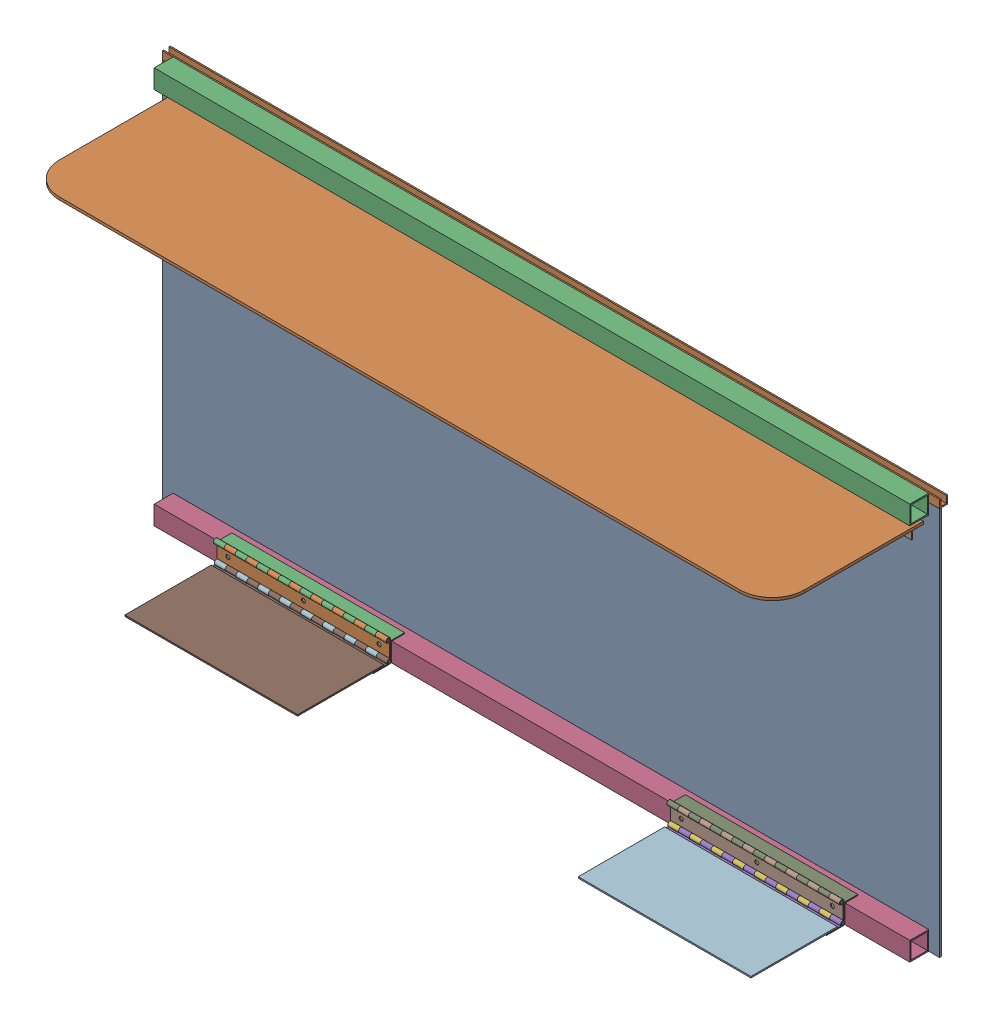
SolidWorks assembly FE-00004_ASM, configuration Default. Lengths in mm.
Overall size (1828.8 933.45 374.65).
43 component instances, 17 part files, 0 mates.
Components (placement in the parent):
- FE-00004-01-1: FE-00004-01 [Default] at origin size (1828.8 914.4 4.76)
- FE-00004-05-1: FE-00004-05 [Default] at (0 914.4 -4.7625) x (1 0 0) z (0 -1 0) size (1828.8 19.05 19.05)
- FE-00004-04-1: FE-00004-04 [Default] at (0 911.225 26.9875) size (1778 44.45 44.45)
- FE-00004-04-2: FE-00004-04 [Default] at (0 22.225 26.9875) size (1778 44.45 44.45)
- FE-00004-02_ASM-1: FE-00004-02_ASM [Default] at (-647.7 858.139 4.7625) x (-1 0 0) z (0 0 -1) size (406.4 43.56 43.56)
  - FE-00004-02-A-1: FE-00004-02-A [Default] at origin size (406.4 43.56 10.92)
  - FE-00004-02-A-2: FE-00004-02-A [Default] at (0 5.461 -5.461) x (-1 0 0) z (0 1 0) size (406.4 43.56 10.92)
  - FE-00004-02-B-1: FE-00004-02-B [Default] at (0 0 -5.461) size (406.4 6.35 6.35)
- FE-00004-02_ASM-2: FE-00004-02_ASM [Default] at (647.7 858.139 4.7625) x (-1 0 0) z (0 0 -1) size (406.4 43.56 43.56)
  - FE-00004-02-A-1: FE-00004-02-A [Default] at origin size (406.4 43.56 10.92)
  - FE-00004-02-A-2: FE-00004-02-A [Default] at (0 5.461 -5.461) x (-1 0 0) z (0 1 0) size (406.4 43.56 10.92)
  - FE-00004-02-B-1: FE-00004-02-B [Default] at (0 0 -5.461) size (406.4 6.35 6.35)
- FE-00004-03_ASM-1: FE-00004-03_ASM [Default] at (0 863.6 10.2235) x (1 0 0) z (0 1 0) size (482.6 43.56 43.56)
  - FE-00004-03-A-1: FE-00004-03-A [Default] at origin size (482.6 43.56 10.92)
  - FE-00004-03-B-1: FE-00004-03-B [Default] at (0 5.461 -5.461) x (-1 0 0) z (0 1 0) size (482.6 43.56 10.92)
  - FE-00004-03-C-1: FE-00004-03-C [Default] at (0 0 -5.461) size (482.6 6.35 6.35)
- FE-00004-06-1: FE-00004-06 [Default] at (127 863.6 182.5625) size (1752.6 6.35 355.6)
- FE-00004-09-1: FE-00004-09 [Default] at (-403.9235 787.4 155.2839) x (1 0 0) z (0 -1 0) size (3.18 302.13 152.4)
- FE-00004-08_ASM-1: FE-00004-08_ASM [Default] at (-400.7485 858.139 179.8901) x (0 0 1) z (-1 0 0) size (203.2 43.56 43.56)
  - FE-00004-08-A-1: FE-00004-08-A [Default] at origin size (203.2 43.56 10.92)
  - FE-00004-08-A-2: FE-00004-08-A [Default] at (0 5.461 -5.461) x (-1 0 0) z (0 1 0) size (203.2 43.56 10.92)
  - FE-00004-08-C-1: FE-00004-08-C [Default] at (0 0 -5.461) size (203.2 6.35 6.35)
- FE-00004-09-2: FE-00004-09 [Default] at (400.7485 787.4 155.2839) x (1 0 0) z (0 -1 0) size (3.18 302.13 152.4)
- FE-00004-08_ASM-2: FE-00004-08_ASM [Default] at (400.7485 858.139 179.8901) x (0 0 -1) z (1 0 0) size (203.2 43.56 43.56)
  - FE-00004-08-A-1: FE-00004-08-A [Default] at origin size (203.2 43.56 10.92)
  - FE-00004-08-A-2: FE-00004-08-A [Default] at (0 5.461 -5.461) x (-1 0 0) z (0 1 0) size (203.2 43.56 10.92)
  - FE-00004-08-C-1: FE-00004-08-C [Default] at (0 0 -5.461) size (203.2 6.35 6.35)
- FE-00004-07_ASM-1: FE-00004-07_ASM [Default] at (-533.4 0 54.6735) x (-1 0 0) z (0 -1 0) size (406.4 73.91 55.37)
  - FE-00004-07-A-1: FE-00004-07-A [Default] at origin size (406.4 43.56 10.92)
  - FE-00004-07-A_AF0-1: FE-00004-07-A_AF0 [Default] at (0 5.461 -5.461) x (-1 0 0) z (0 1 0) size (406.4 43.56 10.92)
  - FE-00004-07-B-1: FE-00004-07-B [Default] at (0 0 -5.461) size (406.4 6.35 6.35)
  - FE-00004-07-A_AF1-1: FE-00004-07-A_AF1 [Default] at (0 3.175 -49.911) x (1 0 0) z (0 1 0) size (406.4 43.56 10.92)
  - FE-00004-07-A-2: FE-00004-07-A [Default] at (0 -2.286 -44.45) x (-1 0 0) z (0 0 1) size (406.4 43.56 10.92)
  - FE-00004-07-B-2: FE-00004-07-B [Default] at (0 -2.286 -49.911) size (406.4 6.35 6.35)
- FE-00004-07_ASM-2: FE-00004-07_ASM [Default] at (533.4 0 54.6735) x (-1 0 0) z (0 -1 0) size (406.4 73.91 55.37)
  - FE-00004-07-A-1: FE-00004-07-A [Default] at origin size (406.4 43.56 10.92)
  - FE-00004-07-A_AF0-1: FE-00004-07-A_AF0 [Default] at (0 5.461 -5.461) x (-1 0 0) z (0 1 0) size (406.4 43.56 10.92)
  - FE-00004-07-B-1: FE-00004-07-B [Default] at (0 0 -5.461) size (406.4 6.35 6.35)
  - FE-00004-07-A_AF1-1: FE-00004-07-A_AF1 [Default] at (0 3.175 -49.911) x (1 0 0) z (0 1 0) size (406.4 43.56 10.92)
  - FE-00004-07-A-2: FE-00004-07-A [Default] at (0 -2.286 -44.45) x (-1 0 0) z (0 0 1) size (406.4 43.56 10.92)
  - FE-00004-07-B-2: FE-00004-07-B [Default] at (0 -2.286 -49.911) size (406.4 6.35 6.35)
- FE-00004-10-1: FE-00004-10 [Default] at (-533.4 2.286 168.9735) size (406.4 3.17 203.2)
- FE-00004-10-2: FE-00004-10 [Default] at (533.4 2.286 168.9735) size (406.4 3.17 203.2)
